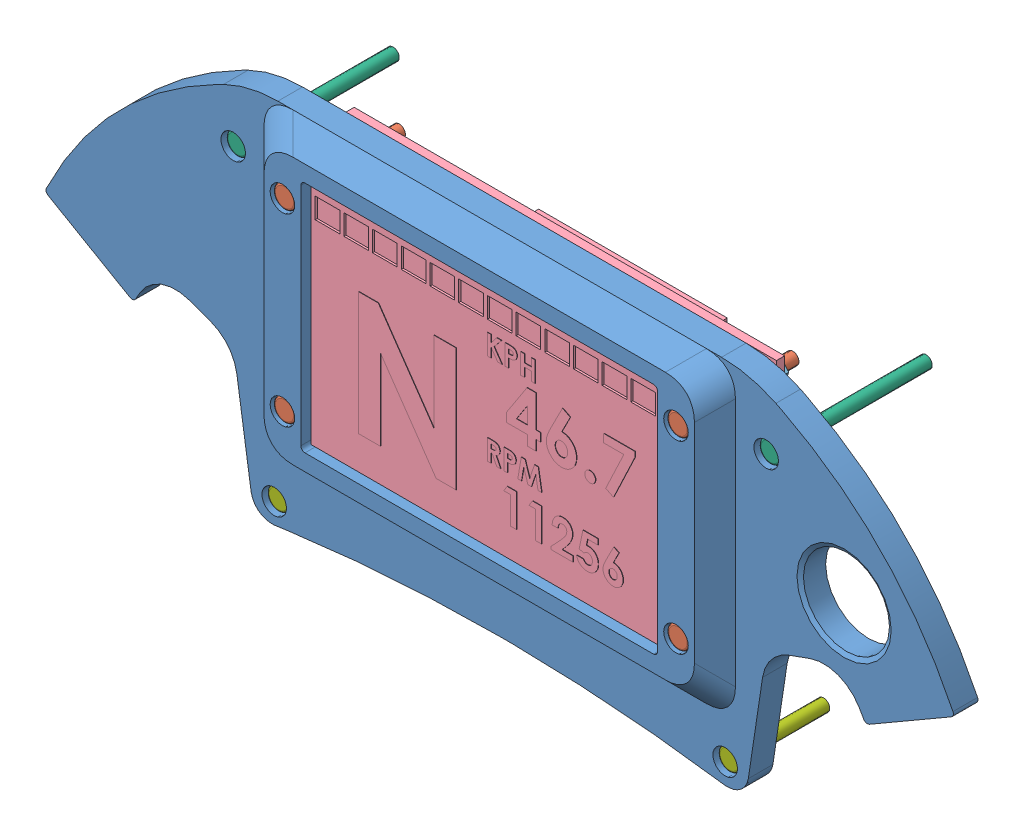
SolidWorks assembly RF019 SWMB&AM, configuration ﾃﾞﾌｫﾙﾄ. Lengths in mm.
Overall size (580 763.75 44).
18 component instances, 7 part files, 44 mates.
Components (placement in the parent):
- RF019 SWMB kai-1: RF019 SWMB kai [ﾃﾞﾌｫﾙﾄ] at (-240.8348 46.0016 758.2468) size (580 763.75 11)
- M3 25 Bolt-1: M3 25 Bolt [ﾃﾞﾌｫﾙﾄ] at (-288.8348 136.0016 768.7468) x (-0.923728 -0.383049 0) z (0 0 -1) size (5.5 5.5 28)
- M3 25 Bolt-2: M3 25 Bolt [ﾃﾞﾌｫﾙﾄ] at (-192.8348 136.0016 768.7468) x (0.997282 -0.073685 0) z (0 0 -1) size (5.5 5.5 28)
- M3 25 Bolt-3: M3 25 Bolt [ﾃﾞﾌｫﾙﾄ] at (-192.8348 91.0016 768.7468) x (0.997282 -0.073685 0) z (0 0 -1) size (5.5 5.5 28)
- M3 25 Bolt-4: M3 25 Bolt [ﾃﾞﾌｫﾙﾄ] at (-288.8348 91.0016 768.7468) x (-0.37219 -0.928157 0) z (0 0 -1) size (5.5 5.5 28)
- RF018 Spacer for SWMB[M3 9]-1: RF018 Spacer for SWMB[M3 9] [ﾃﾞﾌｫﾙﾄ] at (-288.8348 91.0016 749.2468) x (0.899926 -0.436043 0) z (0 0 1) size (8 8 9)
- RF018 Spacer for SWMB[M3 9]-2: RF018 Spacer for SWMB[M3 9] [ﾃﾞﾌｫﾙﾄ] at (-192.8348 91.0016 749.2468) size (8 8 9)
- RF018 Spacer for SWMB[M3 9]-3: RF018 Spacer for SWMB[M3 9] [ﾃﾞﾌｫﾙﾄ] at (-288.8348 136.0016 749.2468) size (8 8 9)
- RF018 Spacer for SWMB[M3 9]-4: RF018 Spacer for SWMB[M3 9] [ﾃﾞﾌｫﾙﾄ] at (-192.8348 136.0016 749.2468) x (0.695312 -0.718708 0) z (0 0 1) size (8 8 9)
- RF019 AC kai Display-1: RF019 AC kai Display [ﾃﾞﾌｫﾙﾄ] at (-240.8348 118.5016 747.2468) size (105 73 36.1)
- M3 Nat-1: M3 Nat [ﾃﾞﾌｫﾙﾄ] at (-192.8348 136.0016 744.8468) x (0.713875 0.700273 0) z (0 0 1) size (5.64 6.34 2.4)
- M3 Nat-2: M3 Nat [ﾃﾞﾌｫﾙﾄ] at (-192.8348 91.0016 744.8468) size (5.64 6.34 2.4)
- M3 Nat-3: M3 Nat [ﾃﾞﾌｫﾙﾄ] at (-288.8348 91.0016 744.8468) size (5.64 6.34 2.4)
- M3 Nat-4: M3 Nat [ﾃﾞﾌｫﾙﾄ] at (-288.8348 136.0016 744.8468) size (5.64 6.34 2.4)
- M3 35 Bolt-1: M3 35 Bolt [ﾃﾞﾌｫﾙﾄ] at (-305.8348 136.0016 763.2468) x (0.923728 0.383049 0) z (0 0 -1) size (5.5 5.5 38)
- M3 35 Bolt-2: M3 35 Bolt [ﾃﾞﾌｫﾙﾄ] at (-175.8348 136.0016 763.2468) x (0.923728 0.383049 0) z (0 0 -1) size (5.5 5.5 38)
- M3 20 Bolt-1: M3 20 Bolt [ﾃﾞﾌｫﾙﾄ] at (-295.8348 66.0016 763.2468) x (0.923728 0.383049 0) z (0 0 -1) size (5.5 5.5 23)
- M3 20 Bolt-2: M3 20 Bolt [ﾃﾞﾌｫﾙﾄ] at (-185.8348 66.0016 763.2468) x (0.923728 0.383049 0) z (0 0 -1) size (5.5 5.5 23)
Mates (geometry in assembly coordinates):
- 同心円1: concentric anti-aligned: cylinder of RF019 SWMB kai-1 through (-288.8348 136.0016 769.2469) axis (0 0 -1) radius 1.75; cylinder of M3 25 Bolt-1 through (-288.8348 136.0016 740.7468) axis (0 0 1) radius 1.5
- 一致1: coincident anti-aligned: plane of RF019 SWMB kai-1 through (-288.8348 136.0016 765.7468) normal (0 0 1); plane of M3 25 Bolt-1 through (-288.8348 136.0016 765.7468) normal (0 0 -1)
- 同心円2: concentric anti-aligned: cylinder of RF019 SWMB kai-1 through (-192.8348 136.0016 769.2469) axis (0 0 -1) radius 1.75; cylinder of M3 25 Bolt-2 through (-192.8348 136.0016 740.7468) axis (0 0 1) radius 1.5
- 一致2: coincident anti-aligned: plane of RF019 SWMB kai-1 through (-192.8348 136.0016 765.7468) normal (0 0 1); plane of M3 25 Bolt-2 through (-192.8348 136.0016 765.7468) normal (0 0 -1)
- 同心円3: concentric anti-aligned: cylinder of RF019 SWMB kai-1 through (-192.8348 91.0016 769.2469) axis (0 0 -1) radius 1.75; cylinder of M3 25 Bolt-3 through (-192.8348 91.0016 740.7468) axis (0 0 1) radius 1.5
- 一致3: coincident anti-aligned: plane of RF019 SWMB kai-1 through (-192.8348 91.0016 765.7468) normal (0 0 1); plane of M3 25 Bolt-3 through (-192.8348 91.0016 765.7468) normal (0 0 -1)
- 同心円4: concentric anti-aligned: cylinder of RF019 SWMB kai-1 through (-288.8348 91.0016 769.2469) axis (0 0 -1) radius 1.75; cylinder of M3 25 Bolt-4 through (-288.8348 91.0016 740.7468) axis (0 0 1) radius 1.5
- 一致4: coincident anti-aligned: plane of RF019 SWMB kai-1 through (-288.8348 91.0016 765.7468) normal (0 0 1); plane of M3 25 Bolt-4 through (-288.8348 91.0016 765.7468) normal (0 0 -1)
- 同心円5: concentric anti-aligned: cylinder of M3 25 Bolt-1 through (-288.8348 136.0016 740.7468) axis (0 0 1) radius 1.5; cylinder of RF018 Spacer for SWMB[M3 9]-3 through (-288.8348 136.0016 758.2468) axis (0 0 -1) radius 2
- 一致5: coincident anti-aligned: plane of RF019 SWMB kai-1 through (-240.8348 46.0016 758.2468) normal (0 0 -1); plane of RF018 Spacer for SWMB[M3 9]-3 through (-288.8348 136.0016 758.2468) normal (0 0 1)
- 同心円6: concentric anti-aligned: cylinder of M3 25 Bolt-4 through (-288.8348 91.0016 740.7468) axis (0 0 1) radius 1.5; cylinder of RF018 Spacer for SWMB[M3 9]-1 through (-288.8348 91.0016 758.2468) axis (0 0 -1) radius 2
- 一致6: coincident anti-aligned: plane of RF019 SWMB kai-1 through (-240.8348 46.0016 758.2468) normal (0 0 -1); plane of RF018 Spacer for SWMB[M3 9]-1 through (-288.8348 91.0016 758.2468) normal (0 0 1)
- 同心円7: concentric anti-aligned: cylinder of M3 25 Bolt-3 through (-192.8348 91.0016 740.7468) axis (0 0 1) radius 1.5; cylinder of RF018 Spacer for SWMB[M3 9]-2 through (-192.8348 91.0016 758.2468) axis (0 0 -1) radius 2
- 一致7: coincident anti-aligned: plane of RF019 SWMB kai-1 through (-240.8348 46.0016 758.2468) normal (0 0 -1); plane of RF018 Spacer for SWMB[M3 9]-2 through (-192.8348 91.0016 758.2468) normal (0 0 1)
- 同心円8: concentric anti-aligned: cylinder of M3 25 Bolt-2 through (-192.8348 136.0016 740.7468) axis (0 0 1) radius 1.5; cylinder of RF018 Spacer for SWMB[M3 9]-4 through (-192.8348 136.0016 758.2468) axis (0 0 -1) radius 2
- 一致8: coincident anti-aligned: plane of RF019 SWMB kai-1 through (-240.8348 46.0016 758.2468) normal (0 0 -1); plane of RF018 Spacer for SWMB[M3 9]-4 through (-192.8348 136.0016 758.2468) normal (0 0 1)
- 同心円15: concentric aligned: cylinder of RF019 SWMB kai-1 through (-192.8348 136.0016 765.7468) axis (0 0 1) radius 3; cylinder of RF019 AC kai Display-1 through (-192.8348 136.0016 747.2468) axis (0 0 1) radius 1.6
- 同心円18: concentric aligned: cylinder of RF019 SWMB kai-1 through (-192.8348 136.0016 765.7468) axis (0 0 1) radius 3; cylinder of RF019 AC kai Display-1 through (-192.8348 136.0016 747.2468) axis (0 0 1) radius 1.6
- 同心円19: concentric aligned: cylinder of RF019 AC kai Display-1 through (-288.8348 136.0016 747.2468) axis (0 0 1) radius 1.6; cylinder of RF019 SWMB kai-1 through (-288.8348 136.0016 765.7468) axis (0 0 1) radius 3
- 一致9: coincident anti-aligned: plane of RF018 Spacer for SWMB[M3 9]-3 through (-288.8348 136.0016 749.2468) normal (0 0 -1); plane of RF019 AC kai Display-1 through (-240.8348 118.5016 749.2468) normal (0 0 1)
- 同心円20: concentric anti-aligned: cylinder of M3 25 Bolt-1 through (-288.8348 136.0016 740.7468) axis (0 0 1) radius 1.5; cylinder of M3 Nat-4 through (-288.8348 136.0016 747.2468) axis (0 0 -1) radius 1.5
- 一致10: coincident anti-aligned: plane of RF019 AC kai Display-1 through (-240.8348 118.5016 747.2468) normal (0 0 -1); plane of M3 Nat-4 through (-288.8348 136.0016 747.2468) normal (0 0 1)
- 同心円21: concentric anti-aligned: cylinder of M3 25 Bolt-4 through (-288.8348 91.0016 740.7468) axis (0 0 1) radius 1.5; cylinder of M3 Nat-3 through (-288.8348 91.0016 747.2468) axis (0 0 -1) radius 1.5
- 一致11: coincident anti-aligned: plane of RF019 AC kai Display-1 through (-240.8348 118.5016 747.2468) normal (0 0 -1); plane of M3 Nat-3 through (-288.8348 91.0016 747.2468) normal (0 0 1)
- 同心円22: concentric anti-aligned: cylinder of M3 25 Bolt-2 through (-192.8348 136.0016 740.7468) axis (0 0 1) radius 1.5; cylinder of M3 Nat-1 through (-192.8348 136.0016 747.2468) axis (0 0 -1) radius 1.5
- 一致12: coincident anti-aligned: plane of RF019 AC kai Display-1 through (-240.8348 118.5016 747.2468) normal (0 0 -1); plane of M3 Nat-1 through (-192.8348 136.0016 747.2468) normal (0 0 1)
- 同心円23: concentric anti-aligned: cylinder of M3 25 Bolt-3 through (-192.8348 91.0016 740.7468) axis (0 0 1) radius 1.5; cylinder of M3 Nat-2 through (-192.8348 91.0016 747.2468) axis (0 0 -1) radius 1.5
- 一致13: coincident anti-aligned: plane of RF019 AC kai Display-1 through (-240.8348 118.5016 747.2468) normal (0 0 -1); plane of M3 Nat-2 through (-192.8348 91.0016 747.2468) normal (0 0 1)
- 同心円24: concentric aligned: cylinder of RF019 SWMB kai-1 through (-305.8348 136.0016 714.2468) axis (0 0 1) radius 1.75; cylinder of M3 35 Bolt-1 through (-305.8348 136.0016 725.2468) axis (0 0 1) radius 1.5
- 一致14: coincident anti-aligned: plane of RF019 SWMB kai-1 through (-305.8348 136.0016 760.2468) normal (0 0 1); plane of M3 35 Bolt-1 through (-305.8348 136.0016 760.2468) normal (0 0 -1)
- 同心円25: concentric aligned: cylinder of RF019 SWMB kai-1 through (-175.8348 136.0016 714.2468) axis (0 0 1) radius 1.75; cylinder of M3 35 Bolt-2 through (-175.8348 136.0016 725.2468) axis (0 0 1) radius 1.5
- 一致15: coincident anti-aligned: plane of RF019 SWMB kai-1 through (-175.8348 136.0016 760.2468) normal (0 0 1); plane of M3 35 Bolt-2 through (-175.8348 136.0016 760.2468) normal (0 0 -1)
- 同心円26: concentric: cylinder of RF019 SWMB kai-1 through (-295.8348 66.0016 714.2468) axis (0 0 1) radius 1.75; cylinder of M3 25 Bolt-5 through (-295.8348 66.0016 735.2468) axis (0 0 1) radius 1.5
- 一致16: coincident anti-aligned: plane of RF019 SWMB kai-1 through (-295.8348 66.0016 760.2468) normal (0 0 1); plane of M3 25 Bolt-5 through (-295.8348 66.0016 760.2468) normal (0 0 -1)
- 同心円27: concentric: cylinder of RF019 SWMB kai-1 through (-185.8348 66.0016 714.2468) axis (0 0 1) radius 1.75; cylinder of M3 25 Bolt-6 through (-185.8348 66.0016 735.2468) axis (0 0 1) radius 1.5
- 一致17: coincident anti-aligned: plane of RF019 SWMB kai-1 through (-185.8348 66.0016 760.2468) normal (0 0 1); plane of M3 25 Bolt-6 through (-185.8348 66.0016 760.2468) normal (0 0 -1)
- 同心円28: concentric aligned: cylinder of RF019 SWMB kai-1 through (-295.8348 66.0016 760.2468) axis (0 0 1) radius 3; cylinder of M3 15 Bolt-1 through (-295.8348 66.0016 745.2468) axis (0 0 1) radius 1.5
- 一致18: coincident anti-aligned: plane of RF019 SWMB kai-1 through (-295.8348 66.0016 760.2468) normal (0 0 1); plane of M3 15 Bolt-1 through (-295.8348 66.0016 760.2468) normal (0 0 -1)
- 同心円29: concentric aligned: cylinder of RF019 SWMB kai-1 through (-185.8348 66.0016 714.2468) axis (0 0 1) radius 1.75; cylinder of M3 15 Bolt-2 through (-185.8348 66.0016 745.2468) axis (0 0 1) radius 1.5
- 一致19: coincident anti-aligned: plane of RF019 SWMB kai-1 through (-185.8348 66.0016 760.2468) normal (0 0 1); plane of M3 15 Bolt-2 through (-185.8348 66.0016 760.2468) normal (0 0 -1)
- 同心円30: concentric aligned: cylinder of RF019 SWMB kai-1 through (-295.8348 66.0016 714.2468) axis (0 0 1) radius 1.75; cylinder of M3 20 Bolt-1 through (-295.8348 66.0016 740.2468) axis (0 0 1) radius 1.5
- 一致20: coincident anti-aligned: plane of RF019 SWMB kai-1 through (-295.8348 66.0016 760.2468) normal (0 0 1); plane of M3 20 Bolt-1 through (-295.8348 66.0016 760.2468) normal (0 0 -1)
- 同心円31: concentric aligned: cylinder of RF019 SWMB kai-1 through (-185.8348 66.0016 714.2468) axis (0 0 1) radius 1.75; cylinder of M3 20 Bolt-2 through (-185.8348 66.0016 740.2468) axis (0 0 1) radius 1.5
- 一致21: coincident anti-aligned: plane of RF019 SWMB kai-1 through (-185.8348 66.0016 760.2468) normal (0 0 1); plane of M3 20 Bolt-2 through (-185.8348 66.0016 760.2468) normal (0 0 -1)
